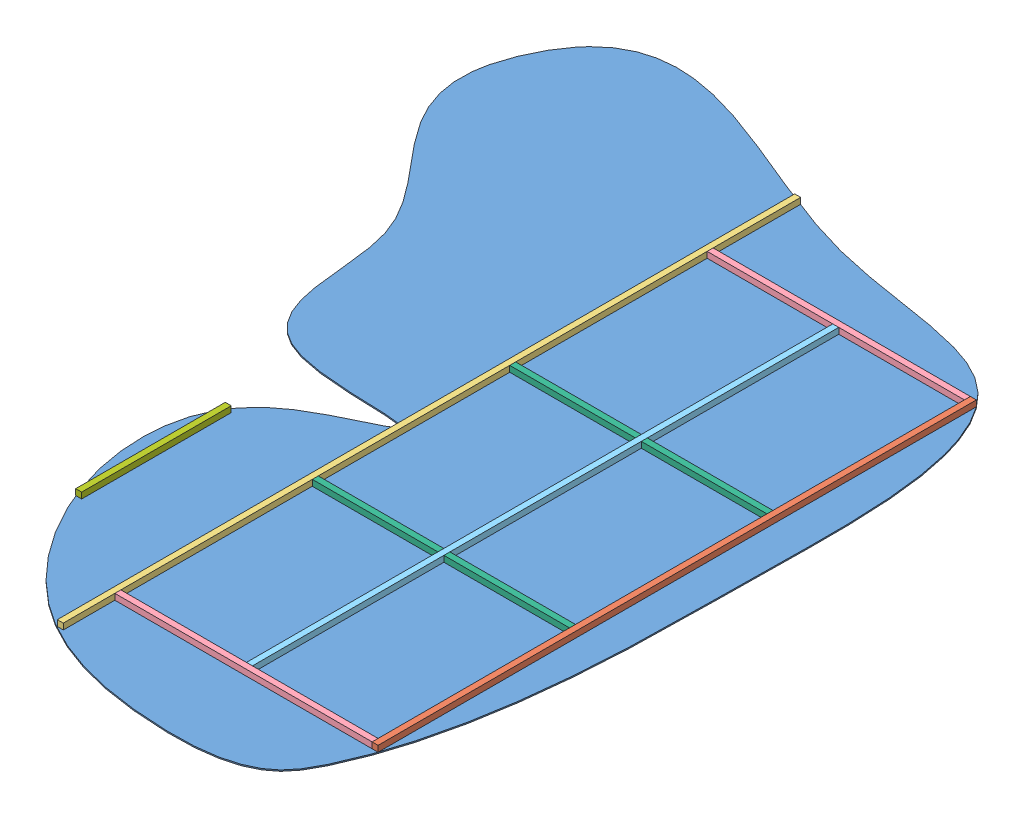
SolidWorks assembly wing_assembly_estimate, configuration Default. Lengths in mm.
Overall size (1971.42 24.13 2800.64).
11 component instances, 7 part files, 35 mates.
Components (placement in the parent):
- wing_photo-1: wing_photo [Default] at (-81.2353 2432.0363 2054.7561) size (1971.42 4.13 2800.64)
- wing_inner_2020-1: wing_inner_2020 [Default] at (2116.5045 2456.1638 2464.4891) x (1 0 0) z (0 -1 0) size (20 2000 20)
- wing_at_split_vertical_2020-2: wing_at_split_vertical_2020 [Default] at (1236.5045 2436.1638 4636.7783) x (1 0 0) z (0 1 0) size (20 2465 20)
- wing_inner_top_2020-1: wing_inner_top_2020 [Default] at (2116.5045 2436.1638 2464.4891) x (0 1 0) z (0 0 1) size (20 860 20)
- wing_inner_top_2020-2: wing_inner_top_2020 [Default] at (2116.5045 2436.1638 4444.4891) x (0 1 0) z (0 0 1) size (20 860 20)
- wing_inner_vertical_brace-1: wing_inner_vertical_brace [Default] at (1676.5045 2436.1638 4444.4891) x (1 0 0) z (0 1 0) size (20 1960 20)
- wing_inner_cross_brace-1: wing_inner_cross_brace [Default] at (1696.5045 2456.1638 3124.4891) x (0 -1 0) z (0 0 1) size (20 420 20)
- wing_inner_cross_brace-2: wing_inner_cross_brace [Default] at (1256.5045 2456.1638 3124.4891) x (0 -1 0) z (0 0 1) size (20 420 20)
- wing_inner_cross_brace-3: wing_inner_cross_brace [Default] at (1696.5045 2456.1638 3784.4891) x (0 -1 0) z (0 0 1) size (20 420 20)
- wing_inner_cross_brace-4: wing_inner_cross_brace [Default] at (1256.5045 2456.1638 3784.4891) x (0 -1 0) z (0 0 1) size (20 420 20)
- 2020_500-2: 2020_500 [Default] at (887.9913 2456.1638 3726.8241) x (1 0 0) z (0 -1 0) size (20 500 20)
Mates (geometry in assembly coordinates):
- Coincident1: coincident: plane of wing_photo-1 through (1698.4156 2436.1638 4754.8693) normal (0 1 0); plane of wing_inner_2020-1 through (2116.5045 2436.1638 4464.4891) normal (0 -1 0)
- Coincident3: coincident: curve of wing_photo-1; point of wing_inner_2020-1
- Coincident4: coincident: curve of wing_photo-1; point of wing_inner_2020-1
- Parallel1: parallel: line of wing_photo-1 through (2261.8914 2436.1638 1982.8926) axis (0 0 1); line of wing_inner_2020-1 through (2136.5045 2436.1638 4464.4891) axis (0 0 -1)
- Parallel2: parallel: line of wing_inner_2020-1 through (2116.5045 2436.1638 4464.4891) axis (0 0 -1); line of ? through (1267.5613 2436.1638 4644.9823) axis (0 0 -1)
- Parallel3: parallel: line of wing_inner_2020-1 through (2116.5045 2436.1638 4464.4891) axis (0 0 -1); line of wing_at_split_vertical_2020-2 through (1256.5045 2436.1638 2171.7783) axis (0 0 1)
- Coincident12: coincident: plane of wing_photo-1 through (1698.4156 2436.1638 4754.8693) normal (0 1 0); plane of wing_at_split_vertical_2020-2 through (1236.5045 2436.1638 2171.7783) normal (0 -1 0)
- Coincident18: coincident: plane of wing_photo-1 through (1698.4156 2436.1638 4754.8693) normal (0 1 0); plane of wing_inner_top_2020-1 through (1256.5045 2436.1638 2464.4891) normal (0 -1 0)
- Coincident19: coincident: plane of wing_inner_2020-1 through (2116.5045 2456.1638 4464.4891) normal (-1 0 0); plane of wing_inner_top_2020-1 through (2116.5045 2436.1638 2464.4891) normal (1 0 0)
- Coincident20: coincident: plane of wing_inner_2020-1 through (2116.5045 2456.1638 2464.4891) normal (0 0 -1); plane of wing_inner_top_2020-1 through (1256.5045 2436.1638 2464.4891) normal (0 0 -1)
- Coincident21: coincident: plane of wing_at_split_vertical_2020-2 through (1256.5045 2436.1638 2171.7783) normal (1 0 0); plane of wing_inner_top_2020-1 through (1256.5045 2436.1638 2464.4891) normal (-1 0 0)
- Coincident22: coincident: plane of wing_photo-1 through (1698.4156 2436.1638 4754.8693) normal (0 1 0); plane of wing_inner_top_2020-2 through (1256.5045 2436.1638 4444.4891) normal (0 -1 0)
- Coincident23: coincident: plane of wing_inner_2020-1 through (2116.5045 2456.1638 4464.4891) normal (-1 0 0); plane of wing_inner_top_2020-2 through (2116.5045 2436.1638 4444.4891) normal (1 0 0)
- Coincident24: coincident: plane of wing_inner_2020-1 through (2116.5045 2456.1638 4464.4891) normal (0 0 1); plane of wing_inner_top_2020-2 through (1256.5045 2436.1638 4464.4891) normal (0 0 1)
- Coincident25: coincident: plane of wing_photo-1 through (1698.4156 2436.1638 4754.8693) normal (0 1 0); plane of wing_inner_vertical_brace-1 through (1676.5045 2436.1638 2484.4891) normal (0 -1 0)
- Coincident26: coincident: plane of wing_inner_top_2020-1 through (1256.5045 2436.1638 2484.4891) normal (0 0 1); plane of wing_inner_vertical_brace-1 through (1676.5045 2436.1638 2484.4891) normal (0 0 -1)
- Coincident27: coincident: plane of wing_photo-1 through (1698.4156 2436.1638 4754.8693) normal (0 1 0); plane of wing_inner_cross_brace-1 through (2116.5045 2436.1638 3124.4891) normal (0 -1 0)
- Coincident28: coincident: plane of wing_inner_2020-1 through (2116.5045 2456.1638 4464.4891) normal (-1 0 0); plane of wing_inner_cross_brace-1 through (2116.5045 2456.1638 3124.4891) normal (1 0 0)
- Coincident30: coincident: plane of wing_inner_vertical_brace-1 through (1696.5045 2436.1638 2484.4891) normal (1 0 0); plane of wing_inner_cross_brace-1 through (1696.5045 2456.1638 3124.4891) normal (-1 0 0)
- Coincident31: coincident: plane of wing_inner_vertical_brace-1 through (1676.5045 2436.1638 2484.4891) normal (-1 0 0); plane of wing_inner_cross_brace-2 through (1676.5045 2456.1638 3124.4891) normal (1 0 0)
- Coincident32: coincident: plane of wing_inner_cross_brace-1 through (2116.5045 2456.1638 3124.4891) normal (0 1 0); plane of wing_inner_cross_brace-2 through (1676.5045 2456.1638 3124.4891) normal (0 1 0)
- Coincident33: coincident: plane of wing_inner_cross_brace-1 through (2116.5045 2456.1638 3124.4891) normal (0 0 -1); plane of wing_inner_cross_brace-2 through (1676.5045 2456.1638 3124.4891) normal (0 0 -1)
- Coincident34: coincident: plane of wing_inner_vertical_brace-1 through (1676.5045 2436.1638 2484.4891) normal (-1 0 0); plane of wing_inner_cross_brace-4 through (1676.5045 2456.1638 3784.4891) normal (1 0 0)
- Coincident35: coincident: plane of wing_inner_vertical_brace-1 through (1676.5045 2456.1638 2484.4891) normal (0 1 0); plane of wing_inner_cross_brace-4 through (1676.5045 2456.1638 3784.4891) normal (0 1 0)
- Coincident36: coincident: plane of wing_inner_cross_brace-3 through (2116.5045 2456.1638 3784.4891) normal (0 1 0); plane of wing_inner_cross_brace-4 through (1676.5045 2456.1638 3784.4891) normal (0 1 0)
- Coincident37: coincident: plane of wing_inner_2020-1 through (2116.5045 2456.1638 4464.4891) normal (-1 0 0); plane of wing_inner_cross_brace-3 through (2116.5045 2456.1638 3784.4891) normal (1 0 0)
- Coincident38: coincident: plane of wing_inner_cross_brace-3 through (2116.5045 2456.1638 3784.4891) normal (0 0 -1); plane of wing_inner_cross_brace-4 through (1676.5045 2456.1638 3784.4891) normal (0 0 -1)
- Distance1: distance = 640 mm: plane of wing_inner_cross_brace-2 through (1676.5045 2456.1638 3124.4891) normal (0 0 -1); plane of wing_inner_top_2020-1 through (1256.5045 2436.1638 2484.4891) normal (0 0 1)
- Distance2: distance = 640 mm: plane of wing_inner_cross_brace-4 through (1676.5045 2456.1638 3804.4891) normal (0 0 1); plane of wing_inner_top_2020-2 through (1256.5045 2436.1638 4444.4891) normal (0 0 -1)
- Coincident41: coincident: plane of wing_photo-1 through (1698.4156 2436.1638 4754.8693) normal (0 1 0); plane of ? through (1236.5045 2436.1638 4189.927) normal (0 -1 0)
- Parallel5: parallel: line of wing_at_split_vertical_2020-2 through (1236.5045 2436.1638 2171.7783) axis (0 0 1); line of ? through (1236.5045 2436.1638 4189.927) axis (0 0 -1)
- Parallel6: parallel: line of wing_at_split_vertical_2020-2 through (1236.5045 2436.1638 2171.7783) axis (0 0 1); line of 2020_500-2 through (907.9913 2456.1638 4226.8241) axis (0 0 -1)
- Coincident44: coincident: plane of wing_at_split_vertical_2020-2 through (1236.5045 2456.1638 2171.7783) normal (0 1 0); plane of 2020_500-2 through (887.9913 2456.1638 4226.8241) normal (0 1 0)
- Coincident45: coincident: curve of wing_photo-1; point of 2020_500-2
- Coincident46: coincident: curve of wing_photo-1; point of 2020_500-2
